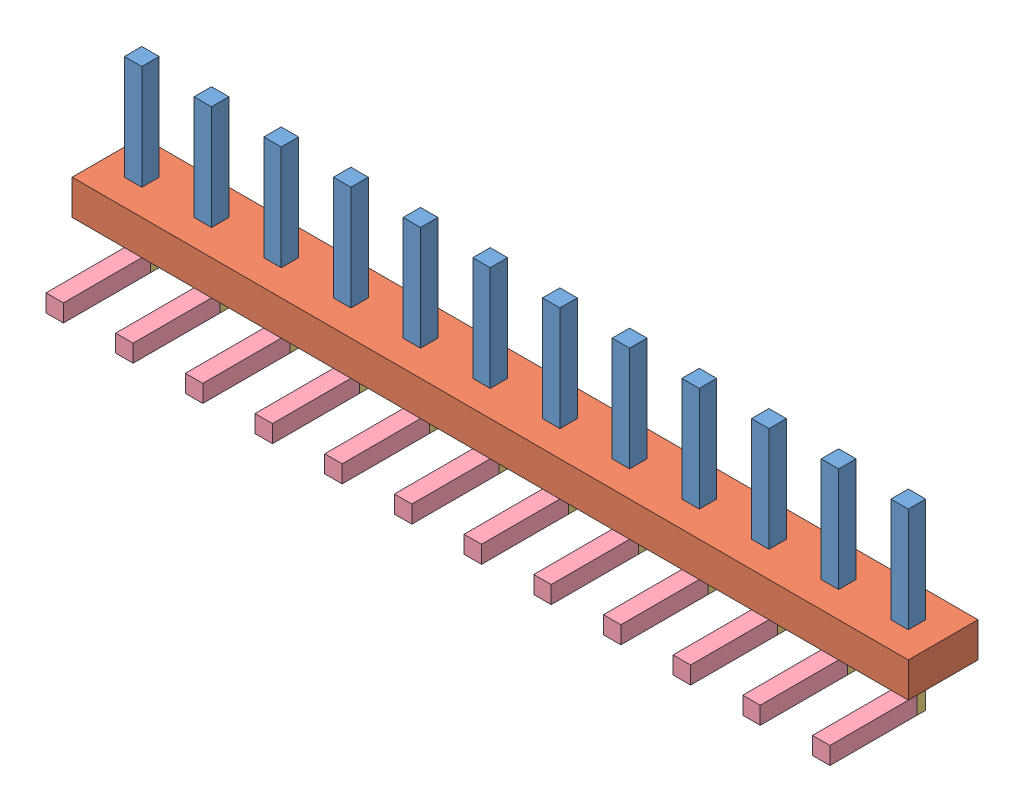
SolidWorks assembly CN401, configuration ﾃﾞﾌｫﾙﾄ. Lengths in mm.
Overall size (24 5.25 3.5).
74 component instances, 4 part files, 0 mates.
Components (placement in the parent):
- 689264232-1: 689264232 [ﾃﾞﾌｫﾙﾄ] at (72 87.35 -2.4503) size (0.5 3 0.5)
  - Extruded_17-1: Extruded_17 [ﾃﾞﾌｫﾙﾄ] at origin size (0.5 3 0.5)
- 689264368-1: 689264368 [ﾃﾞﾌｫﾙﾄ] at (61.125 85.35 -3.2003) size (24.25 1 2)
  - Extruded_18-1: Extruded_18 [ﾃﾞﾌｫﾙﾄ] at origin size (24.25 1 2)
- 689264504-1: 689264504 [ﾃﾞﾌｫﾙﾄ] at (71.9999 84.2251 -2.4503) size (0.5 1.25 0.5)
  - Extruded_19-1: Extruded_19 [ﾃﾞﾌｫﾙﾄ] at origin size (0.5 1.25 0.5)
- 689264640-1: 689264640 [ﾃﾞﾌｫﾙﾄ] at (72 83.8501 -2.2003) size (0.5 0.5 2.5)
  - Extruded_20-1: Extruded_20 [ﾃﾞﾌｫﾙﾄ] at origin size (0.5 0.5 2.5)
- 689264640-2: 689264640 [ﾃﾞﾌｫﾙﾄ] at (70 83.8501 -2.2003) size (0.5 0.5 2.5)
  - Extruded_20-1: Extruded_20 [ﾃﾞﾌｫﾙﾄ] at origin size (0.5 0.5 2.5)
- 689264504-2: 689264504 [ﾃﾞﾌｫﾙﾄ] at (69.9999 84.2251 -2.4503) size (0.5 1.25 0.5)
  - Extruded_19-1: Extruded_19 [ﾃﾞﾌｫﾙﾄ] at origin size (0.5 1.25 0.5)
- 689264640-3: 689264640 [ﾃﾞﾌｫﾙﾄ] at (68 83.8501 -2.2003) size (0.5 0.5 2.5)
  - Extruded_20-1: Extruded_20 [ﾃﾞﾌｫﾙﾄ] at origin size (0.5 0.5 2.5)
- 689264504-3: 689264504 [ﾃﾞﾌｫﾙﾄ] at (67.9999 84.2251 -2.4503) size (0.5 1.25 0.5)
  - Extruded_19-1: Extruded_19 [ﾃﾞﾌｫﾙﾄ] at origin size (0.5 1.25 0.5)
- 689264640-4: 689264640 [ﾃﾞﾌｫﾙﾄ] at (66 83.8501 -2.2003) size (0.5 0.5 2.5)
  - Extruded_20-1: Extruded_20 [ﾃﾞﾌｫﾙﾄ] at origin size (0.5 0.5 2.5)
- 689264504-4: 689264504 [ﾃﾞﾌｫﾙﾄ] at (65.9999 84.2251 -2.4503) size (0.5 1.25 0.5)
  - Extruded_19-1: Extruded_19 [ﾃﾞﾌｫﾙﾄ] at origin size (0.5 1.25 0.5)
- 689264640-5: 689264640 [ﾃﾞﾌｫﾙﾄ] at (64 83.8501 -2.2003) size (0.5 0.5 2.5)
  - Extruded_20-1: Extruded_20 [ﾃﾞﾌｫﾙﾄ] at origin size (0.5 0.5 2.5)
- 689264504-5: 689264504 [ﾃﾞﾌｫﾙﾄ] at (63.9999 84.2251 -2.4503) size (0.5 1.25 0.5)
  - Extruded_19-1: Extruded_19 [ﾃﾞﾌｫﾙﾄ] at origin size (0.5 1.25 0.5)
- 689264640-6: 689264640 [ﾃﾞﾌｫﾙﾄ] at (62 83.8501 -2.2003) size (0.5 0.5 2.5)
  - Extruded_20-1: Extruded_20 [ﾃﾞﾌｫﾙﾄ] at origin size (0.5 0.5 2.5)
- 689264504-6: 689264504 [ﾃﾞﾌｫﾙﾄ] at (61.9999 84.2251 -2.4503) size (0.5 1.25 0.5)
  - Extruded_19-1: Extruded_19 [ﾃﾞﾌｫﾙﾄ] at origin size (0.5 1.25 0.5)
- 689264640-7: 689264640 [ﾃﾞﾌｫﾙﾄ] at (60 83.8501 -2.2003) size (0.5 0.5 2.5)
  - Extruded_20-1: Extruded_20 [ﾃﾞﾌｫﾙﾄ] at origin size (0.5 0.5 2.5)
- 689264504-7: 689264504 [ﾃﾞﾌｫﾙﾄ] at (59.9999 84.2251 -2.4503) size (0.5 1.25 0.5)
  - Extruded_19-1: Extruded_19 [ﾃﾞﾌｫﾙﾄ] at origin size (0.5 1.25 0.5)
- 689264640-8: 689264640 [ﾃﾞﾌｫﾙﾄ] at (58 83.8501 -2.2003) size (0.5 0.5 2.5)
  - Extruded_20-1: Extruded_20 [ﾃﾞﾌｫﾙﾄ] at origin size (0.5 0.5 2.5)
- 689264504-8: 689264504 [ﾃﾞﾌｫﾙﾄ] at (57.9999 84.2251 -2.4503) size (0.5 1.25 0.5)
  - Extruded_19-1: Extruded_19 [ﾃﾞﾌｫﾙﾄ] at origin size (0.5 1.25 0.5)
- 689264640-9: 689264640 [ﾃﾞﾌｫﾙﾄ] at (56 83.8501 -2.2003) size (0.5 0.5 2.5)
  - Extruded_20-1: Extruded_20 [ﾃﾞﾌｫﾙﾄ] at origin size (0.5 0.5 2.5)
- 689264504-9: 689264504 [ﾃﾞﾌｫﾙﾄ] at (55.9999 84.2251 -2.4503) size (0.5 1.25 0.5)
  - Extruded_19-1: Extruded_19 [ﾃﾞﾌｫﾙﾄ] at origin size (0.5 1.25 0.5)
- 689264640-10: 689264640 [ﾃﾞﾌｫﾙﾄ] at (54 83.8501 -2.2003) size (0.5 0.5 2.5)
  - Extruded_20-1: Extruded_20 [ﾃﾞﾌｫﾙﾄ] at origin size (0.5 0.5 2.5)
- 689264504-10: 689264504 [ﾃﾞﾌｫﾙﾄ] at (53.9999 84.2251 -2.4503) size (0.5 1.25 0.5)
  - Extruded_19-1: Extruded_19 [ﾃﾞﾌｫﾙﾄ] at origin size (0.5 1.25 0.5)
- 689264640-11: 689264640 [ﾃﾞﾌｫﾙﾄ] at (52 83.8501 -2.2003) size (0.5 0.5 2.5)
  - Extruded_20-1: Extruded_20 [ﾃﾞﾌｫﾙﾄ] at origin size (0.5 0.5 2.5)
- 689264504-11: 689264504 [ﾃﾞﾌｫﾙﾄ] at (51.9999 84.2251 -2.4503) size (0.5 1.25 0.5)
  - Extruded_19-1: Extruded_19 [ﾃﾞﾌｫﾙﾄ] at origin size (0.5 1.25 0.5)
- 689264640-12: 689264640 [ﾃﾞﾌｫﾙﾄ] at (50 83.8501 -2.2003) size (0.5 0.5 2.5)
  - Extruded_20-1: Extruded_20 [ﾃﾞﾌｫﾙﾄ] at origin size (0.5 0.5 2.5)
- 689264504-12: 689264504 [ﾃﾞﾌｫﾙﾄ] at (49.9999 84.2251 -2.4503) size (0.5 1.25 0.5)
  - Extruded_19-1: Extruded_19 [ﾃﾞﾌｫﾙﾄ] at origin size (0.5 1.25 0.5)
- 689264232-2: 689264232 [ﾃﾞﾌｫﾙﾄ] at (70 87.35 -2.4503) size (0.5 3 0.5)
  - Extruded_17-1: Extruded_17 [ﾃﾞﾌｫﾙﾄ] at origin size (0.5 3 0.5)
- 689264232-3: 689264232 [ﾃﾞﾌｫﾙﾄ] at (68 87.35 -2.4503) size (0.5 3 0.5)
  - Extruded_17-1: Extruded_17 [ﾃﾞﾌｫﾙﾄ] at origin size (0.5 3 0.5)
- 689264232-4: 689264232 [ﾃﾞﾌｫﾙﾄ] at (66 87.35 -2.4503) size (0.5 3 0.5)
  - Extruded_17-1: Extruded_17 [ﾃﾞﾌｫﾙﾄ] at origin size (0.5 3 0.5)
- 689264232-5: 689264232 [ﾃﾞﾌｫﾙﾄ] at (64 87.35 -2.4503) size (0.5 3 0.5)
  - Extruded_17-1: Extruded_17 [ﾃﾞﾌｫﾙﾄ] at origin size (0.5 3 0.5)
- 689264232-6: 689264232 [ﾃﾞﾌｫﾙﾄ] at (62 87.35 -2.4503) size (0.5 3 0.5)
  - Extruded_17-1: Extruded_17 [ﾃﾞﾌｫﾙﾄ] at origin size (0.5 3 0.5)
- 689264232-7: 689264232 [ﾃﾞﾌｫﾙﾄ] at (60 87.35 -2.4503) size (0.5 3 0.5)
  - Extruded_17-1: Extruded_17 [ﾃﾞﾌｫﾙﾄ] at origin size (0.5 3 0.5)
- 689264232-8: 689264232 [ﾃﾞﾌｫﾙﾄ] at (58 87.35 -2.4503) size (0.5 3 0.5)
  - Extruded_17-1: Extruded_17 [ﾃﾞﾌｫﾙﾄ] at origin size (0.5 3 0.5)
- 689264232-9: 689264232 [ﾃﾞﾌｫﾙﾄ] at (56 87.35 -2.4503) size (0.5 3 0.5)
  - Extruded_17-1: Extruded_17 [ﾃﾞﾌｫﾙﾄ] at origin size (0.5 3 0.5)
- 689264232-10: 689264232 [ﾃﾞﾌｫﾙﾄ] at (54 87.35 -2.4503) size (0.5 3 0.5)
  - Extruded_17-1: Extruded_17 [ﾃﾞﾌｫﾙﾄ] at origin size (0.5 3 0.5)
- 689264232-11: 689264232 [ﾃﾞﾌｫﾙﾄ] at (52 87.35 -2.4503) size (0.5 3 0.5)
  - Extruded_17-1: Extruded_17 [ﾃﾞﾌｫﾙﾄ] at origin size (0.5 3 0.5)
- 689264232-12: 689264232 [ﾃﾞﾌｫﾙﾄ] at (50 87.35 -2.4503) size (0.5 3 0.5)
  - Extruded_17-1: Extruded_17 [ﾃﾞﾌｫﾙﾄ] at origin size (0.5 3 0.5)
